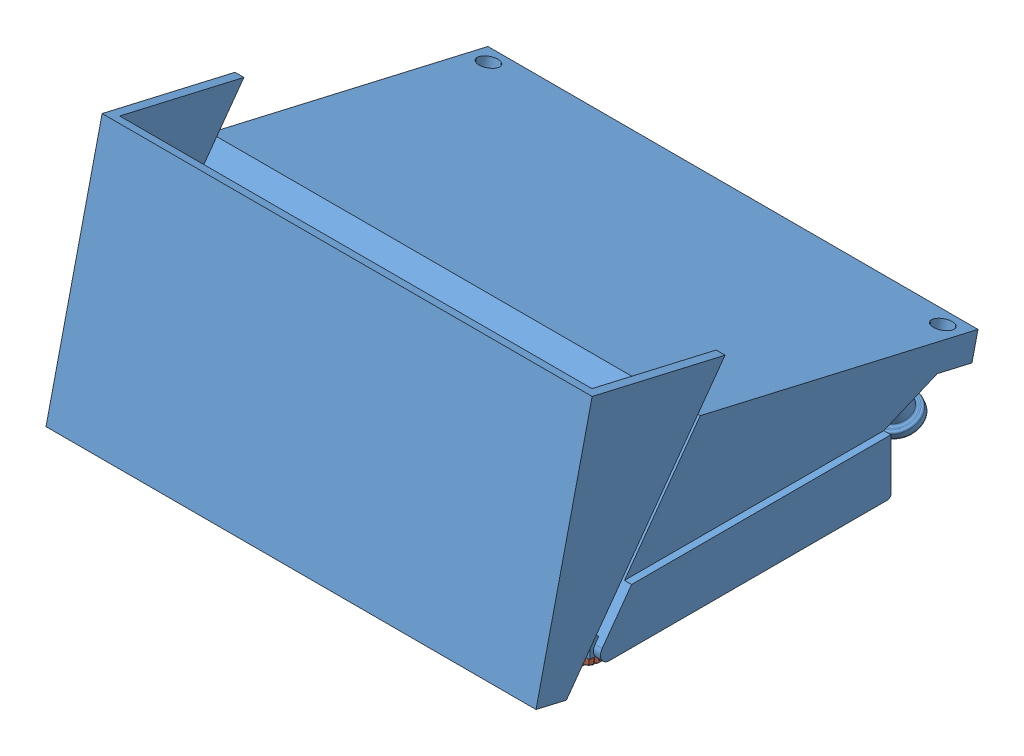
SolidWorks assembly UFC_REF, configuration Default. Lengths in mm.
Overall size (179.71 93.17 157.5).
36 component instances, 5 part files, 0 mates.
Components (placement in the parent):
- UFC and HUD Ref v3-1: UFC and HUD Ref v3 [Default] at origin size (179.71 89.12 157.5)
- MS21382.f3d v5-1: MS21382.f3d v5 [Default] at (-74.295 -178.9284 113.9667) x (-1 0 0) z (0 -1 0) size (15.78 14.05 12.77)
- MS21382.f3d v5-2: MS21382.f3d v5 [Default] at (73.025 -178.9284 113.9667) x (-1 0 0) z (0 -1 0) size (15.78 14.05 12.77)
- MS21382.f3d v5-3: MS21382.f3d v5 [Default] at (73.025 -178.9284 159.0517) x (-1 0 0) z (0 -1 0) size (15.78 14.05 12.77)
- 92141A008-1: 92141A008 [Default] at (6.731 -179.9444 74.2792) (suppressed, hidden)
- 92141A008-2: 92141A008 [Default] at (81.28 -179.9444 124.6982) (suppressed, hidden)
- 92141A008-3: 92141A008 [Default] at (6.731 -179.9444 175.8792) (suppressed, hidden)
- 92141A008-4: 92141A008 [Default] at (-81.28 -179.9444 124.6982) (suppressed, hidden)
- 91249A148-1: 91249A148 [Default] at (6.731 -167.2444 175.8792) x (1 0 0) z (0 -1 0) (suppressed, hidden)
- 91249A148-2: 91249A148 [Default] at (6.731 -167.2444 74.2792) x (1 0 0) z (0 -1 0) (suppressed, hidden)
- 91249A148-3: 91249A148 [Default] at (81.28 -167.2444 124.6982) x (1 0 0) z (0 -1 0) (suppressed, hidden)
- 91249A148-4: 91249A148 [Default] at (-81.28 -167.2444 124.6982) x (1 0 0) z (0 -1 0) (suppressed, hidden)
- 92141A008-5: 92141A008 [Default] at (-42.545 -164.7044 43.0055) (suppressed, hidden)
- 92141A008-6: 92141A008 [Default] at (42.545 -164.7044 43.0055) (suppressed, hidden)
- 91249A148-5: 91249A148 [Default] at (-42.545 -152.0044 43.0055) x (1 0 0) z (0 -1 0) (suppressed, hidden)
- 91249A148-6: 91249A148 [Default] at (42.545 -152.0044 43.0055) x (1 0 0) z (0 -1 0) (suppressed, hidden)
- 91251A081-1: 91251A081 [Default] at (22.86 -170.394 175.7522) x (1 0 0) z (0 1 0) size (3.56 3.56 15.02)
- 91251A081-2: 91251A081 [Default] at (55.88 -170.394 175.7522) x (1 0 0) z (0 1 0) size (3.56 3.56 15.02)
- 91251A081-3: 91251A081 [Default] at (22.86 -170.394 155.4322) x (1 0 0) z (0 1 0) size (3.56 3.56 15.02)
- 91251A081-4: 91251A081 [Default] at (55.88 -170.394 155.4322) x (1 0 0) z (0 1 0) size (3.56 3.56 15.02)
- 91251A081-5: 91251A081 [Default] at (22.86 -170.394 135.1122) x (1 0 0) z (0 1 0) size (3.56 3.56 15.02)
- 91251A081-6: 91251A081 [Default] at (55.88 -170.394 135.1122) x (1 0 0) z (0 1 0) size (3.56 3.56 15.02)
- 91251A081-7: 91251A081 [Default] at (55.88 -170.394 74.1522) x (1 0 0) z (0 1 0) size (3.56 3.56 15.02)
- 91251A081-8: 91251A081 [Default] at (55.88 -170.394 114.7922) x (1 0 0) z (0 1 0) size (3.56 3.56 15.02)
- 91251A081-9: 91251A081 [Default] at (22.86 -170.394 94.4722) x (1 0 0) z (0 1 0) size (3.56 3.56 15.02)
- 91251A081-10: 91251A081 [Default] at (55.88 -170.394 94.4722) x (1 0 0) z (0 1 0) size (3.56 3.56 15.02)
- 91251A081-11: 91251A081 [Default] at (22.86 -170.394 74.1522) x (1 0 0) z (0 1 0) size (3.56 3.56 15.02)
- 91251A081-12: 91251A081 [Default] at (22.86 -170.394 114.7922) x (1 0 0) z (0 1 0) size (3.56 3.56 15.02)
- 91251A081-13: 91251A081 [Default] at (-56.8325 -170.394 175.7522) x (1 0 0) z (0 1 0) size (3.56 3.56 15.02)
- 91251A081-14: 91251A081 [Default] at (-9.2075 -170.394 175.7522) x (1 0 0) z (0 1 0) size (3.56 3.56 15.02)
- 91251A081-15: 91251A081 [Default] at (-56.8325 -170.394 155.4322) x (1 0 0) z (0 1 0) size (3.56 3.56 15.02)
- 91251A081-16: 91251A081 [Default] at (-9.2075 -170.394 155.4322) x (1 0 0) z (0 1 0) size (3.56 3.56 15.02)
- 91251A081-17: 91251A081 [Default] at (73.66 -170.394 74.1522) x (1 0 0) z (0 1 0) size (3.56 3.56 15.02)
- 91251A081-18: 91251A081 [Default] at (-73.66 -170.394 94.4722) x (1 0 0) z (0 1 0) size (3.56 3.56 15.02)
- 91251A081-19: 91251A081 [Default] at (73.66 -170.394 94.4722) x (1 0 0) z (0 1 0) size (3.56 3.56 15.02)
- 91251A081-20: 91251A081 [Default] at (-73.66 -170.394 74.1522) x (1 0 0) z (0 1 0) size (3.56 3.56 15.02)
